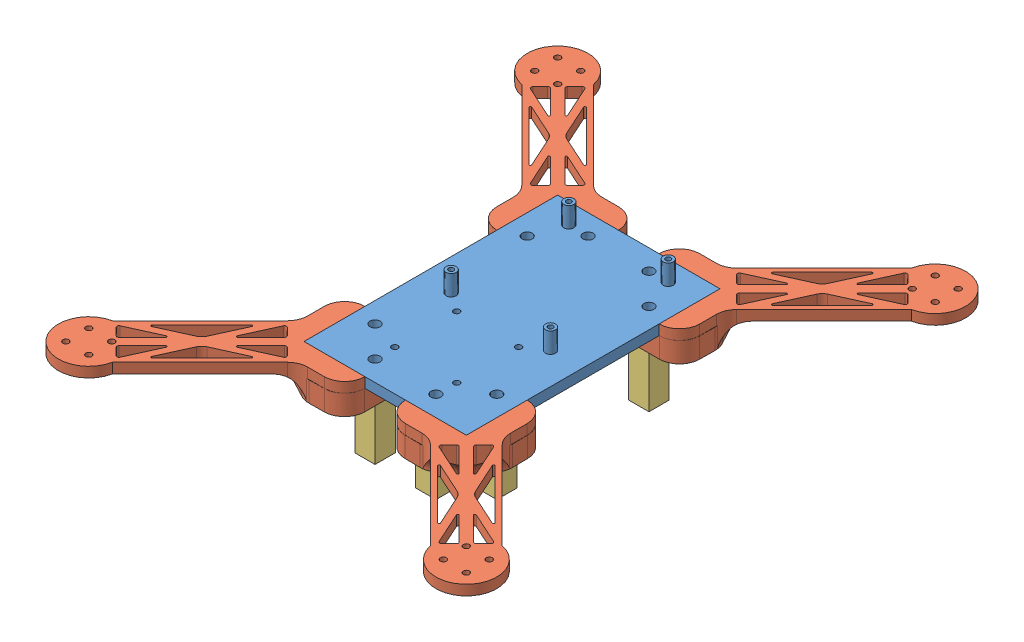
SolidWorks assembly NewAssembly_1, configuration Default. Lengths in mm.
Overall size (241.5 50 286.5).
9 component instances, 3 part files, 24 mates.
Components (placement in the parent):
- NewBasePlate-1: NewBasePlate [Default] at (48.801 62.6408 91.4829) size (80 15 125)
- NewArm_1-1: NewArm_1 [Default] at (88.801 62.6408 28.9829) x (0.707107 0 -0.707107) z (0.707107 0 0.707107) size (121.82 15 48.4)
- NewArm_1-2: NewArm_1 [Default] at (88.801 62.6408 153.9829) x (0.707107 0 0.707107) z (-0.707107 0 0.707107) size (121.82 15 48.4)
- NewArm_1-3: NewArm_1 [Default] at (8.801 62.6408 28.9829) x (-0.707107 0 -0.707107) z (0.707107 0 -0.707107) size (121.82 15 48.4)
- NewArm_1-4: NewArm_1 [Default] at (8.801 62.6408 153.9829) x (-0.707107 0 0.707107) z (-0.707107 0 -0.707107) size (121.82 15 48.4)
- VerticalSpacer-1: VerticalSpacer [Default] at (63.801 27.6408 53.9829) size (25 25 25)
- VerticalSpacer-2: VerticalSpacer [Default] at (33.801 27.6408 128.9829) x (-1 0 0) z (0 0 -1) size (25 25 25)
- VerticalSpacer-3: VerticalSpacer [Default] at (63.801 27.6408 128.9829) x (0 0 1) z (-1 0 0) size (25 25 25)
- VerticalSpacer-4: VerticalSpacer [Default] at (33.801 27.6408 53.9829) x (0 0 -1) z (1 0 0) size (25 25 25)
Mates (geometry in assembly coordinates):
- Coincident1: coincident anti-aligned: plane of NewBasePlate-1 through (48.801 62.6408 91.4829) normal (0 -1 0); plane of NewArm_1-1 through (68.801 62.6408 28.9063) normal (0 1 0)
- Coincident2: coincident anti-aligned: plane of NewBasePlate-1 through (48.801 62.6408 91.4829) normal (0 -1 0); plane of NewArm_1-2 through (88.8776 62.6408 133.9829) normal (0 1 0)
- Coincident3: coincident anti-aligned: plane of NewBasePlate-1 through (48.801 62.6408 91.4829) normal (0 -1 0); plane of NewArm_1-3 through (8.7244 62.6408 48.9829) normal (0 1 0)
- Coincident4: coincident anti-aligned: plane of NewBasePlate-1 through (48.801 62.6408 91.4829) normal (0 -1 0); plane of NewArm_1-4 through (28.801 62.6408 154.0595) normal (0 1 0)
- Concentric1: concentric anti-aligned: circle of NewBasePlate-1; circle of NewArm_1-4
- Concentric2: concentric anti-aligned: circle of NewBasePlate-1; circle of NewArm_1-4
- Concentric3: concentric anti-aligned: circle of NewBasePlate-1; circle of NewArm_1-2
- Concentric4: concentric anti-aligned: circle of NewBasePlate-1; circle of NewArm_1-2
- Concentric5: concentric anti-aligned: circle of NewBasePlate-1; circle of NewArm_1-3
- Concentric6: concentric anti-aligned: circle of NewBasePlate-1; circle of NewArm_1-3
- Concentric7: concentric anti-aligned: circle of NewBasePlate-1; circle of NewArm_1-1
- Concentric8: concentric anti-aligned: circle of NewBasePlate-1; circle of NewArm_1-1
- Concentric10: concentric aligned: circle of NewBasePlate-1; circle of VerticalSpacer-1
- Concentric11: concentric aligned: circle of NewBasePlate-1; circle of VerticalSpacer-1
- Coincident9: coincident anti-aligned: plane of NewArm_1-1 through (49.4048 52.6408 -51.7661) normal (0 -1 0); plane of VerticalSpacer-1 through (63.801 52.6408 53.9829) normal (0 1 0)
- Coincident10: coincident anti-aligned: plane of NewArm_1-4 through (48.1971 52.6408 234.7319) normal (0 -1 0); plane of VerticalSpacer-2 through (33.801 52.6408 128.9829) normal (0 1 0)
- Concentric13: concentric aligned: circle of NewBasePlate-1; circle of VerticalSpacer-2
- Concentric14: concentric aligned: circle of NewBasePlate-1; circle of VerticalSpacer-2
- Coincident14: coincident anti-aligned: plane of NewArm_1-2 through (169.5499 52.6408 114.5867) normal (0 -1 0); plane of VerticalSpacer-3 through (63.801 52.6408 128.9829) normal (0 1 0)
- Concentric15: concentric anti-aligned: circle of NewArm_1-2; circle of VerticalSpacer-3
- Concentric16: concentric anti-aligned: circle of NewArm_1-2; circle of VerticalSpacer-3
- Coincident17: coincident: plane of NewArm_1-3 through (-71.948 52.6408 68.3791) normal (0 -1 0); plane of VerticalSpacer-4 through (33.801 52.6408 53.9829) normal (0 1 0)
- Concentric17: concentric: circle of NewArm_1-3; circle of VerticalSpacer-4
- Concentric19: concentric anti-aligned: circle of NewArm_1-3; circle of VerticalSpacer-4
